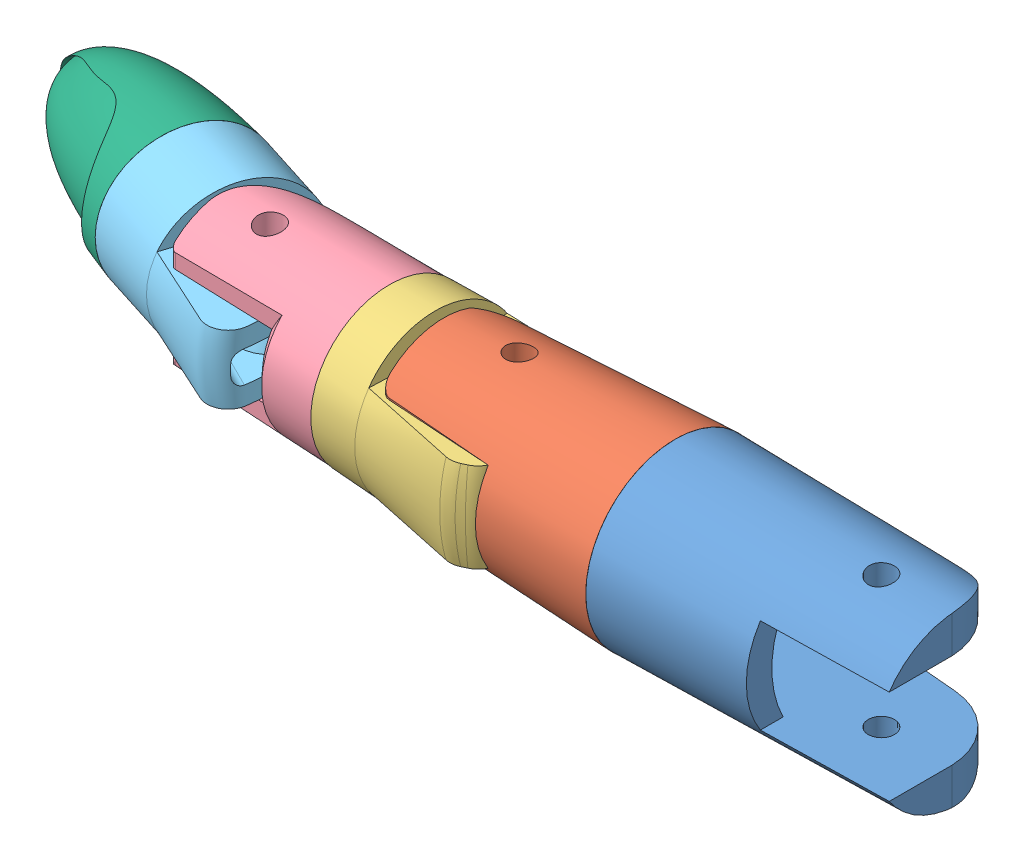
SolidWorks assembly deget mijlociu, configuration Default. Lengths in mm.
Overall size (101.44 17.94 26.5).
6 component instances, 6 part files, 18 mates.
Components (placement in the parent):
- major3-4-1: major3-4 [Default] x (0 -1 0) z (0 0 1) size (17.93 28.49 17.93)
- major3-3-1: major3-3 [Default] at origin size (23.21 17.94 17.94)
- major3-5-1: major3-5 [Default] at (-28.8122 0 -0.4421) x (0.999391 0 0.034899) z (0 -1 0) size (18.44 17.85 16.26)
- major3-6-1: major3-6 [Default] at (-45.6819 0 -1.0313) x (0.999391 0 0.034899) z (0.034899 0 -0.999391) size (16.88 16.16 15.75)
- major3-2-1: major3-2 [Default] at (-53.3574 0 -4.4512) x (-0.303003 0 0.952989) z (0.952989 0 0.303003) size (15.56 14.88 19.06)
- articulatiemijlociu3-1: articulatiemijlociu3 [Default] at (-53.3587 0 -4.4471) x (0 1 0) z (-0.303003 0 0.952989) size (14.79 18.22 14.79)
Mates (geometry in assembly coordinates):
- Coincident1: coincident aligned: plane of major3-4-1 through (0 0 0) normal (0 0 1)
- Coincident2: coincident aligned: plane of major3-4-1 through (0 0 0) normal (1 0 0)
- Coincident3: coincident anti-aligned: plane of major3-4-1 through (0 0 0) normal (0 -1 0)
- Concentric1: concentric anti-aligned: cone of major3-4-1 through (0 0 0) axis (1 0 0); cone of major3-3-1 through (-23.21 0 0) axis (-1 0 0)
- Coincident4: coincident anti-aligned: plane of major3-4-1 through (0 0 0) normal (-1 0 0); plane of major3-3-1 through (0 0 0) normal (1 0 0)
- Coincident5: coincident aligned: plane of major3-4-1 through (0 0 0) normal (0 0 1); plane of major3-3-1 through (0 0 0) normal (0 0 1)
- Concentric2: concentric anti-aligned: cylinder of major3-3-1 through (-16.1415 -10.55 -0.5275) axis (0 1 0) radius 1.3188; cylinder of major3-5-1 through (-16.1415 8.131 -0.5275) axis (0 -1 0) radius 1.3188
- Coincident6: coincident anti-aligned: plane of major3-3-1 through (-26.3539 4.4837 -10.55) normal (0 -1 0); plane of major3-5-1 through (-18.0042 4.4837 1.1793) normal (0 1 0)
- LimitAngle1: limit planar angle = 3.106686 rad anti-aligned: plane of major3-3-1 through (0 0 0) normal (0 0 1); plane of major3-5-1 through (-28.8122 0 -0.4421) normal (-0.034899 0 0.999391)
- Concentric3: concentric aligned: cone of major3-5-1 through (-28.8122 0 -0.4421) axis (-0.999391 0 -0.034899); cone of major3-6-1 through (-26.7035 0 -0.3685) axis (-0.999391 0 -0.034899)
- Coincident7: coincident aligned: circle of major3-5-1; plane of major3-6-1 through (-29.0883 24.5287 7.4655) normal (0.999391 0 0.034899)
- Coincident8: coincident anti-aligned: plane of major3-5-1 through (-28.8122 0 -0.4421) normal (-0.034899 0 0.999391); plane of major3-6-1 through (-45.6819 0 -1.0313) normal (0.034899 0 -0.999391)
- Concentric4: concentric aligned: cylinder of major3-6-1 through (-40.4469 7.9125 0.2072) axis (0 -1 0) radius 1.3188; cylinder of major3-2-1 through (-40.4469 7.4378 0.2072) axis (0 -1 0) radius 1.3188
- Coincident9: coincident anti-aligned: plane of major3-6-1 through (-45.6819 3.4287 -1.0313) normal (0 -1 0); plane of major3-2-1 through (-38.914 3.4287 5.9334) normal (0 1 0)
- LimitAngle2: limit planar angle = 0.272936 rad anti-aligned: plane of major3-6-1 through (-45.6819 0 -1.0313) normal (0.034899 0 -0.999391); plane of major3-2-1 through (-53.3574 0 -4.4512) normal (-0.303003 0 0.952989)
- Coincident11: coincident anti-aligned: cylinder of major3-2-1 through (-45.8168 0 -2.0537) axis (-0.952989 0 -0.303003) radius 7.385; circle of articulatiemijlociu3-1
- Coincident12: coincident anti-aligned: plane of major3-2-1 through (-53.3574 0 -4.4512) normal (-0.952989 0 -0.303003); plane of articulatiemijlociu3-1 through (-51.7987 0 -9.3535) normal (0.952989 0 0.303003)
- Parallel1: parallel aligned: plane of major3-2-1 through (-53.3574 0 -4.4512) normal (-0.303003 0 0.952989); plane of articulatiemijlociu3-1 through (-53.3587 0 -4.4471) normal (-0.303003 0 0.952989)
